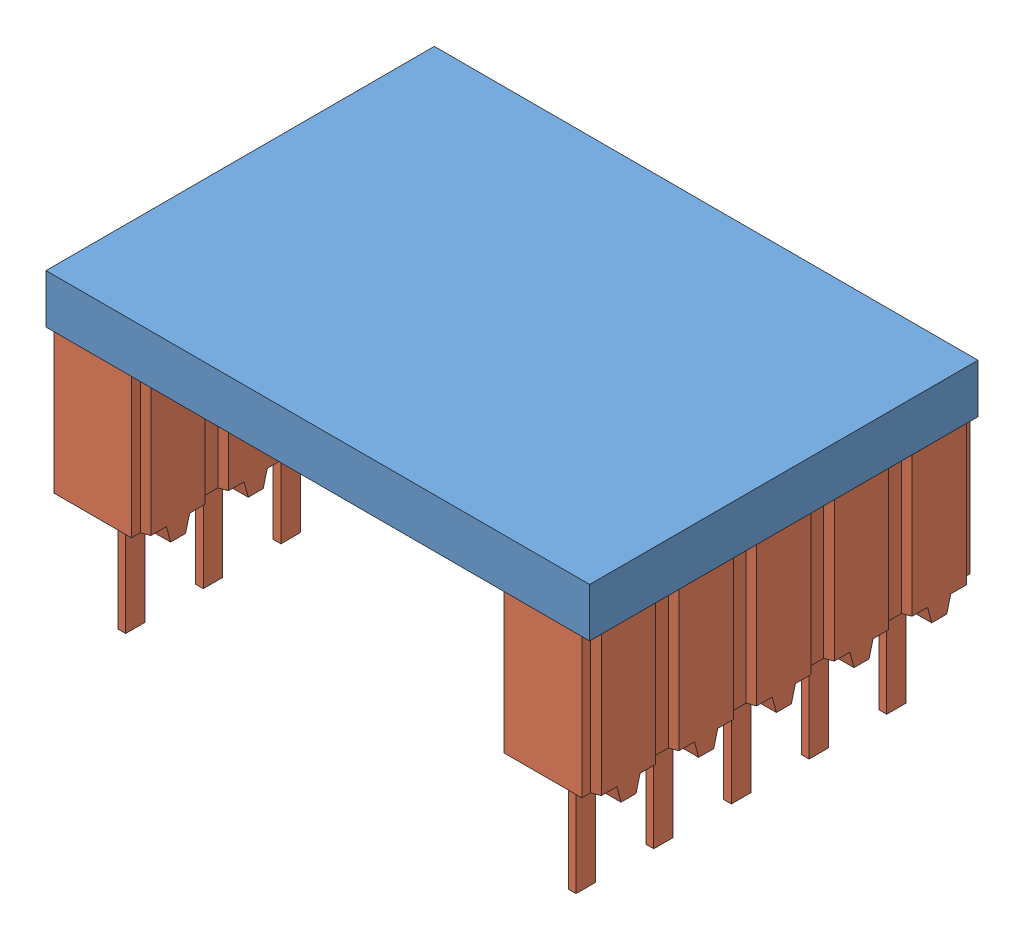
SolidWorks assembly IMU, configuration Default. Lengths in mm.
Overall size (17.78 9.93 12.7).
3 component instances, 2 part files, 8 mates.
Components (placement in the parent):
- Part3^IMU-1: Part3^IMU [Default] at (-14.7144 5.08 6.1216) x (0 0 -1) z (0 1 0) size (12.7 17.78 1.6) (virtual)
- CES-105-01-S-S-1: CES-105-01-S-S [Default] at (0.4012 0 6.35) x (0 0 -1) z (1 0 0) size (12.7 8.33 3.05)
- CES-105-01-S-S-2: CES-105-01-S-S [Default] at (-14.3308 0 6.35) x (0 0 -1) z (1 0 0) size (12.7 8.33 3.05)
Mates (geometry in assembly coordinates):
- Coincident16: coincident anti-aligned: plane of Part3^IMU-1 through (-14.7144 0 6.1216) normal (0 -1 0); plane of CES-105-01-S-S-1 through (0.4012 0 6.35) normal (0 1 0)
- Coincident17: coincident aligned: plane of Part3^IMU-1 through (-15.8548 1.6 0) normal (0 0 -1); plane of CES-105-01-S-S-1 through (1.9252 0 0) normal (0 0 -1)
- Coincident18: coincident aligned: plane of Part3^IMU-1 through (1.9252 1.6 0) normal (1 0 0); plane of CES-105-01-S-S-1 through (1.9252 0 12.7) normal (1 0 0)
- Coincident21: coincident anti-aligned: plane of ? through (-15.8548 1.6 0) normal (0 0 -1)
- Coincident22: coincident aligned: plane of Part3^IMU-1 through (-15.8548 1.6 12.7) normal (0 0 1); plane of CES-105-01-S-S-2 through (-15.8548 0 12.7) normal (0 0 1)
- Coincident23: coincident anti-aligned: plane of Part3^IMU-1 through (-14.7144 0 6.1216) normal (0 -1 0); plane of CES-105-01-S-S-2 through (-14.3308 0 6.35) normal (0 1 0)
- Coincident24: coincident aligned: plane of Part3^IMU-1 through (-15.8548 1.6 0) normal (-1 0 0); plane of CES-105-01-S-S-2 through (-15.8548 0 0) normal (-1 0 0)
- Coincident25: coincident anti-aligned: plane of CES-105-01-S-S-1 through (0.4012 0 6.35) normal (0 -1 0); plane of assembly
